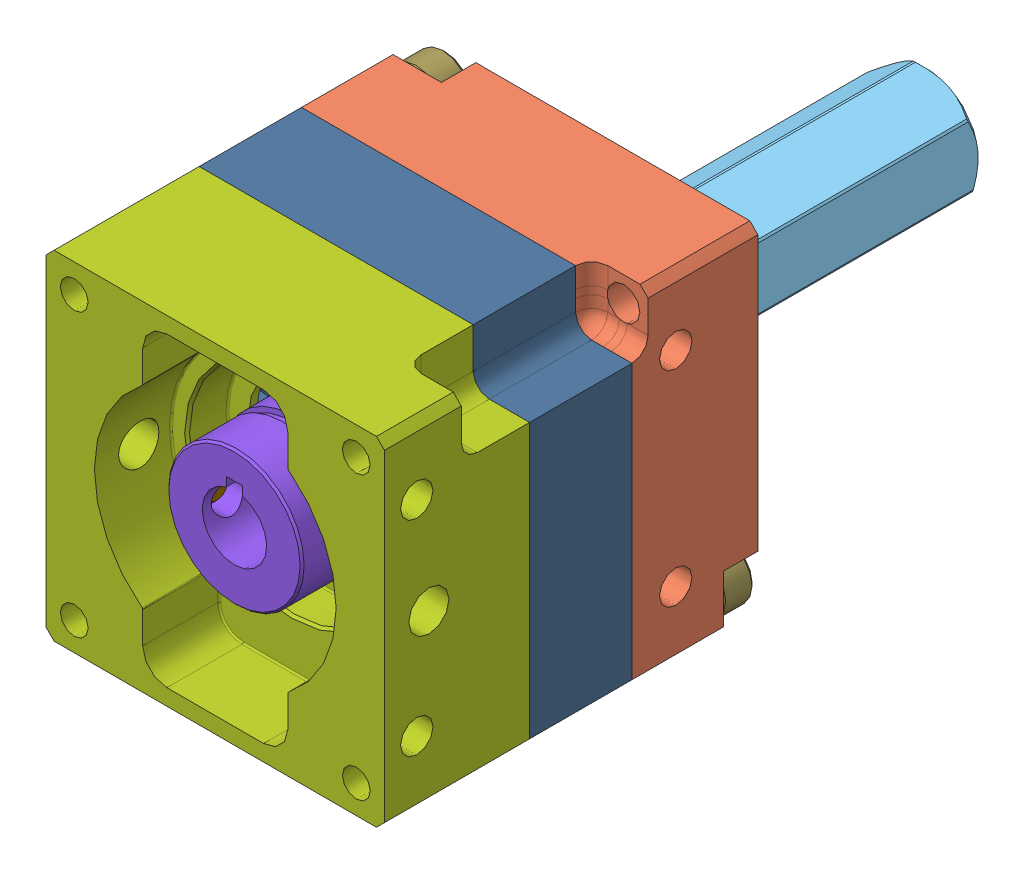
SolidWorks assembly VersaPlanetary_v1_Single_Stage_10_1, configuration Default. Lengths in mm.
Overall size (62.06 62.06 160.81).
22 component instances, 15 part files, 0 mates.
Components (placement in the parent):
- 217-2742-001 Rev4-1: 217-2742-001 Rev4 [Default] at (0 0 -19.9002) x (0 0 1) z (-1 0 0) size (7 28 28)
- 217-2742-001 Rev4-2: 217-2742-001 Rev4 [Default] at (0 0 -28.305) x (0 0 1) z (-0.819238 -0.573454 0) size (7 28 28)
- 217-2625-002 Rev1-1: 217-2625-002 Rev1 [Default] at (0 0 -6.2) x (-1 0 0) z (0 0 1) size (42 42 17.13)
- 217-2625-018 Rev1_98541A410-1: 217-2625-018 Rev1_98541A410 [Default] at (0 0 -12.4002) x (0 0 -1) z (0.980859 -0.194721 0) size (1 19.6 17.4)
- 217-2625-017 Rev1_9714K61-1: 217-2625-017 Rev1_9714K61 [Default] at (0 0 -20.9002) x (-0.695225 0.718792 0) z (-0.718792 -0.695225 0) size (28.51 4.98 30.18)
- Ouput Shafts^VersaPlanetary_500 Hex-1: Ouput Shafts^VersaPlanetary_500 Hex [Default] at (0 0 -20.5526) x (-0.995515 -0.094608 0) z (0 0 -1) size (17 17 64.12)
  - 217-2625-003 Rev1-1: 217-2625-003 Rev1 [Default] at origin size (17 17 64.12)
- 217-3564-000 Rev1_BAG-1: 217-3564-000 Rev1_BAG [Default] at (0 0 18) size (42 42 81.5) (hidden)
  - 217-2625-011 Rev1-1: 217-2625-011 Rev1 [Default] at (0 0 -5.25) x (1 0 0) z (0 -1 0) size (8.01 7.5 7.94)
  - 217-2822-003 Rev4-1: 217-2822-003 Rev4 [Default] at (0 0 1.5) size (42 42 4.8)
  - 217-3351-1: 217-3351 [Default] at (0 0 3) x (0 1 0) z (0 0 -1) size (40.4 40.4 81.5)
- Input Housing^VersaPlanetary-1: Input Housing^VersaPlanetary [Default] at (-18.5 13.6657 1) x (0 0 -1) z (-0.885621 0.464408 0) size (20 56.7 56.7)
  - PINL-M020-006-S-1: PINL-M020-006-S [Default] at origin size (6 2 2)
  - 217-2625-001 Rev1-1: 217-2625-001 Rev1 [Default] at (-9.5 3.511 -22.7304) x (0 -0.464408 -0.885621) z (-1 0 0) size (42 42 18)
  - 217-2625-009 Rev1-1: 217-2625-009 Rev1 [Default] at (-6.02 3.511 -22.7304) x (0 0.885621 -0.464408) z (1 0 0) size (18 18 13)
  - SSS1032-0125ZB_94105A824-1: SSS1032-0125ZB_94105A824 [Default] at (-11.495 6.7192 -16.6126) x (-0.636804 0.682837 -0.35807) z (0 0.464408 0.885621) size (4.83 4.84 3.3)
- 217-2816 Rev1-1: 217-2816 Rev1 [Default] at (0 0 -6.35) x (1 0 0) z (0 0 -1) size (42 42 14.5)
  - 217-2816-001 Rev1-1: 217-2816-001 Rev1 [Default] at origin size (42 42 14.5)
- 217-2817 Rev1-1: 217-2817 Rev1 [Default] at (0 0 -10.8) x (-0.517538 0.85566 0) z (0 0 -1) size (21.94 21.95 12.7)
  - 217-2724-001 Rev1_Sun_Driver01-1: 217-2724-001 Rev1_Sun_Driver01 [Default] at (0 0 -6.375) x (0.984808 0.173648 0) z (0 0 1) size (18.94 18.95 12.7)
- SSA_SSA0832-1250ZC-1: SSA_SSA0832-1250ZC [Default] at (-17.5 17.5 -24.061) x (0.699203 0.714923 0) z (-0.714923 0.699203 0) size (6.73 35.81 6.73)
- SSA_SSA0832-1250ZC-2: SSA_SSA0832-1250ZC [Default] at (17.5 -17.5 -24.061) x (-0.999999 0.001665 0) z (-0.001665 -0.999999 0) size (6.73 35.81 6.73)
